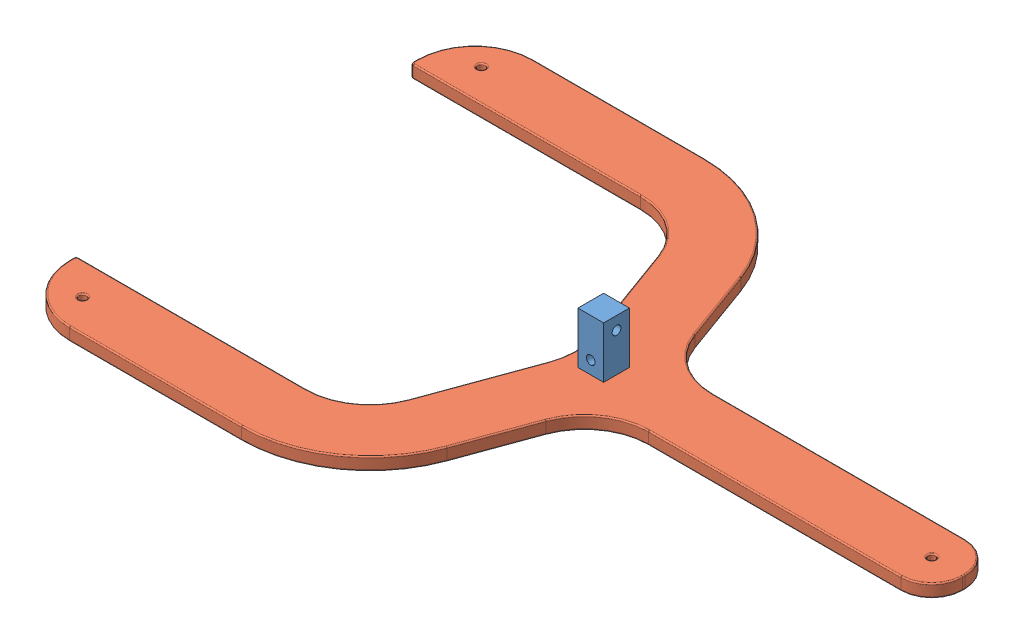
SolidWorks assembly Assemblage2, configuration Défaut. Lengths in mm.
Overall size (560 50 360).
2 component instances, 2 part files, 3 mates.
Components (placement in the parent):
- Carré plein 20x20X50-1: Carré plein 20x20X50 [Défaut] at origin size (20 50 20)
- Fourche design-1: Fourche design [Défaut] at (30 5 -10) size (560 10 360)
Mates (geometry in assembly coordinates):
- Coïncidente1: coincident: plane of Carré plein 20x20X50-1 through (0 0 0) normal (-1 0 0); plane of Fourche design-1 through (0 13.4593 -20) normal (1 0 0)
- Coïncidente2: coincident: plane of Carré plein 20x20X50-1 through (20 5 0) normal (0 0 1); plane of Fourche design-1 through (0 13.4593 0) normal (0 0 -1)
- Coïncidente3: coincident aligned: plane of Carré plein 20x20X50-1 through (20 5 -20) normal (0 -1 0); plane of Fourche design-1 through (30 5 -10) normal (0 -1 0)
